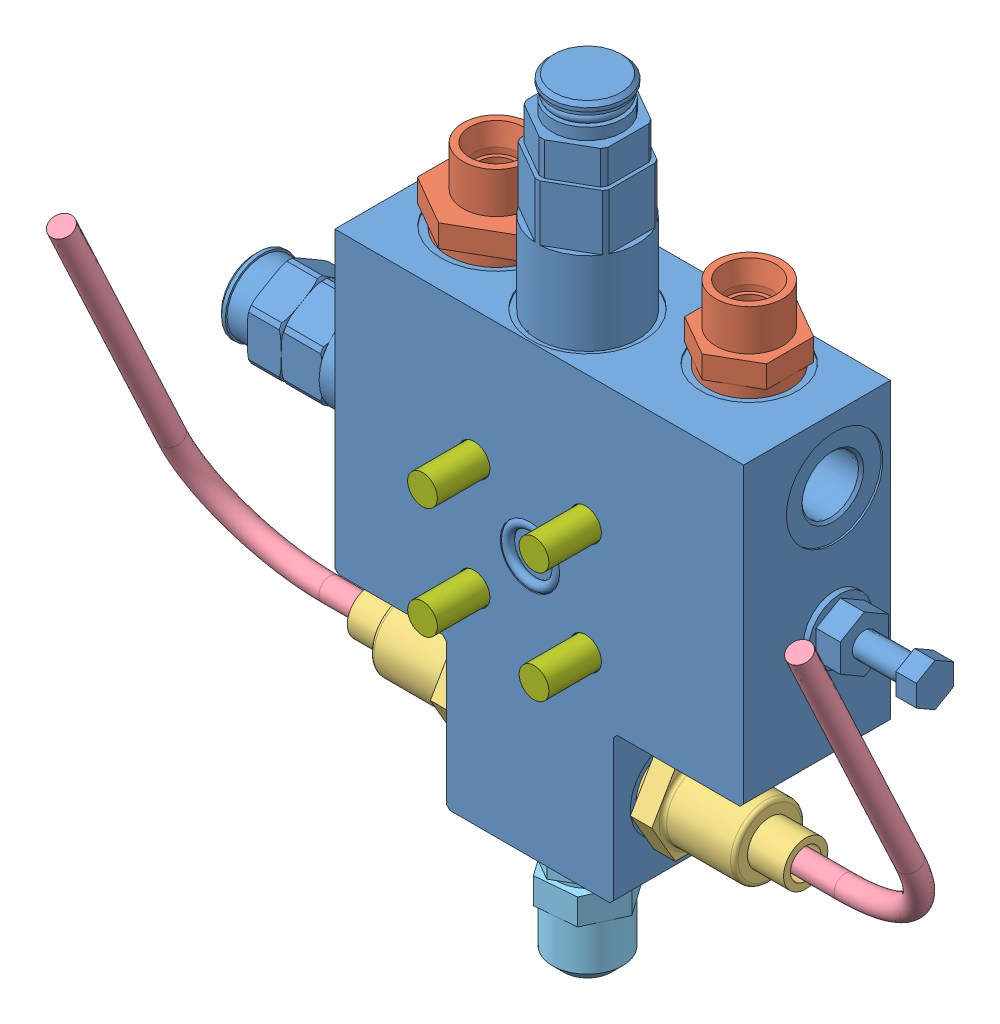
SolidWorks assembly Lastholdeventil Vip 55227 med dele, configuration Default. Lengths in mm.
Overall size (204.6 206.3 75.88).
16 component instances, 7 part files, 49 mates.
Components (placement in the parent):
- 55227-1: 55227 [Default] at origin size (183 174.8 39.85)
- Lige forskruninger-1: Lige forskruninger [P-GEV 12 LR-WD - 25127] at (87 58.5 0) x (1 0 0) z (0 -1 0) size (22 25.4 32)
- Lige forskruninger-2: Lige forskruninger [P-GES 12 LR 1-2 - WD - 25108] at (21 58.5 2) x (1 0 0) z (0 -1 0) size (27 31.18 34)
- 28850-1: 28850 [Default] at (111.2 -50 9) x (-1 0 0) z (0 0 1) size (47.5 21.71 25)
- 28850-2: 28850 [Default] at (-6.2 -50 9) x (1 0 0) z (0 0 -1) size (47.5 21.71 25)
- Ledning-1: Ledning [Default] at (3.2 -50 9) x (0 -0.422618 0.906308) z (1 0 0) size (6 103 53)
- Ledning-2: Ledning [Default] at (101.8 -50 9) x (0 0.422618 -0.906308) z (-1 0 0) size (6 103 53)
- Testnippel-1: Testnippel [26103] at (52.5 -77.5 9) x (1 0 0) z (0 1 0) size (21.85 21.94 41.5)
- Skiver-1: Skiver [Planskive 8mm A2 - 31147] at (67.5 -15 -15) x (1 0 0) z (0 0 -1) size (16 16 1.6)
- Skiver-2: Skiver [Planskive 8mm A2 - 31147] at (67.5 15 -15) x (1 0 0) z (0 0 -1) size (16 16 1.6)
- Skiver-3: Skiver [Planskive 8mm A2 - 31147] at (37.5 15 -15) x (1 0 0) z (0 0 -1) size (16 16 1.6)
- Skiver-4: Skiver [Planskive 8mm A2 - 31147] at (37.5 -15 -15) x (1 0 0) z (0 0 -1) size (16 16 1.6)
- Stålbolte-1: Stålbolte [M8 x 55 Rustfri - 30140] at (67.5 -15 -21.9) x (-1 0 0) z (0 0 1) size (15.01 13 60.3)
- Stålbolte-2: Stålbolte [M8 x 55 Rustfri - 30140] at (67.5 15 -21.9) x (-1 0 0) z (0 0 1) size (15.01 13 60.3)
- Stålbolte-3: Stålbolte [M8 x 55 Rustfri - 30140] at (37.5 15 -21.9) x (-1 0 0) z (0 0 1) size (15.01 13 60.3)
- Stålbolte-4: Stålbolte [M8 x 55 Rustfri - 30140] at (37.5 -15 -21.9) x (-0.5 -0.866025 0) z (0 0 1) size (15.01 13 60.3)
Mates (geometry in assembly coordinates):
- Concentric1: concentric anti-aligned: cylinder of 28850-1 through (111.2 -50 9) axis (1 0 0) radius 6.5; cylinder of 55227-1 through (16.858 -50 9) axis (-1 0 0) radius 5.9
- Coincident1: coincident anti-aligned: plane of 28850-1 through (74.5 -56.5 9) normal (-1 0 0); plane of 55227-1 through (74.5 -43.4 9) normal (1 0 0)
- Concentric2: concentric aligned: cylinder of 55227-1 through (16.858 -50 9) axis (-1 0 0) radius 5.9; cylinder of 28850-2 through (-6.2 -50 9) axis (-1 0 0) radius 6.5
- Coincident2: coincident anti-aligned: plane of 55227-1 through (30.5 -43.4 9) normal (-1 0 0); plane of 28850-2 through (30.5 -56.5 9) normal (1 0 0)
- Coincident3: coincident anti-aligned: plane of 55227-1 through (52.5 -69.5 15.6) normal (0 -1 0); plane of Testnippel-1 through (52.5 -69.5 9) normal (0 1 0)
- Concentric3: concentric anti-aligned: cylinder of 55227-1 through (52.5 -30 9) axis (0 1 0) radius 5.9; cylinder of Testnippel-1 through (52.5 -60 9) axis (0 -1 0) radius 6.5785
- Coincident5: coincident anti-aligned: plane of 28850-1 through (101.8 -54.1 9) normal (1 0 0); plane of Ledning-2 through (101.8 -50 9) normal (-1 0 0)
- Concentric5: concentric anti-aligned: cylinder of 28850-1 through (111.2 -50 9) axis (1 0 0) radius 4.1; cylinder of Ledning-2 through (121.8 -50 9) axis (-1 0 0) radius 3
- Concentric6: concentric anti-aligned: cylinder of 28850-2 through (-6.2 -50 9) axis (-1 0 0) radius 4.1; cylinder of Ledning-1 through (-16.8 -50 9) axis (1 0 0) radius 3
- Coincident6: coincident anti-aligned: plane of 28850-2 through (3.2 -54.1 9) normal (-1 0 0); plane of Ledning-1 through (3.2 -50 9) normal (1 0 0)
- Coincident7: coincident anti-aligned: plane of Ledning-1 through (3.2 -50 9) normal (0 -0.422618 0.906308); plane of Ledning-2 through (101.8 -50 9) normal (0 0.422618 -0.906308)
- Concentric7: concentric anti-aligned: cylinder of Skiver-1 through (67.5 -15 -16.6) axis (0 0 1) radius 8; cylinder of Stålbolte-1 through (67.5 -15 38.4) axis (0 0 -1) radius 4
- Coincident8: coincident anti-aligned: plane of Skiver-1 through (67.5 -15 -16.6) normal (0 0 -1); plane of Stålbolte-1 through (63.7472 -8.5 -16.6) normal (0 0 1)
- Concentric8: concentric anti-aligned: cylinder of Skiver-2 through (67.5 15 -16.6) axis (0 0 1) radius 8; cylinder of Stålbolte-2 through (67.5 15 38.4) axis (0 0 -1) radius 4
- Coincident9: coincident anti-aligned: plane of Skiver-2 through (67.5 15 -16.6) normal (0 0 -1); plane of Stålbolte-2 through (63.7472 21.5 -16.6) normal (0 0 1)
- Concentric9: concentric anti-aligned: cylinder of Skiver-3 through (37.5 15 -16.6) axis (0 0 1) radius 4.2; cylinder of Stålbolte-3 through (37.5 15 38.4) axis (0 0 -1) radius 4
- Coincident10: coincident anti-aligned: plane of Skiver-3 through (37.5 15 -16.6) normal (0 0 -1); plane of Stålbolte-3 through (33.7472 21.5 -16.6) normal (0 0 1)
- Coincident11: coincident anti-aligned: plane of Skiver-4 through (37.5 -15 -16.6) normal (0 0 -1); plane of Stålbolte-4 through (29.9944 -15 -16.6) normal (0 0 1)
- Coincident12: coincident aligned: plane of 55227-1 through (0 0 0) normal (0 0 1); plane of assembly through (0 0 0) normal (0 0 1)
- Coincident13: coincident aligned: plane of 55227-1 through (0 0 0) normal (0 1 0); plane of assembly through (0 0 0) normal (0 1 0)
- Coincident14: coincident aligned: plane of 55227-1 through (0 0 0) normal (1 0 0); plane of assembly through (0 0 0) normal (1 0 0)
- Concentric10: concentric anti-aligned: cylinder of 55227-1 through (87 12.903 0) axis (0 -1 0) radius 7.625; cylinder of Lige forskruninger-1 through (87 37.5 0) axis (0 1 0) radius 8.331
- Coincident15: coincident anti-aligned: plane of 55227-1 through (87 49.5 -13) normal (0 1 0); plane of Lige forskruninger-1 through (87 49.5 0) normal (0 -1 0)
- Concentric11: concentric aligned: cylinder of 55227-1 through (21 57.522 2) axis (0 1 0) radius 9.5; cylinder of Lige forskruninger-2 through (21 35.5 2) axis (0 1 0) radius 10.4975
- Coincident16: coincident anti-aligned: plane of 55227-1 through (21 49.5 -8.2) normal (0 1 0); plane of Lige forskruninger-2 through (21 49.5 2) normal (0 -1 0)
- Coincident17: coincident anti-aligned: plane of 28850-1 through (111.2 -50 9) normal (0 0 1); plane of 28850-2 through (-6.2 -50 9) normal (0 0 -1)
- Coincident18: coincident aligned: plane of Lige forskruninger-1 through (87 58.5 0) normal (0 0 1); plane of assembly through (0 0 0) normal (0 0 1)
- Parallel1: parallel aligned: plane of Lige forskruninger-2 through (21 58.5 2) normal (0 0 1); plane of assembly through (0 0 0) normal (0 0 1)
- Parallel2: parallel anti-aligned: plane of 28850-1 through (111.2 -50 9) normal (0 -1 0); plane of assembly through (0 0 0) normal (0 1 0)
- Coincident23: coincident aligned: plane of Ledning-1 through (3.2 -50 9) normal (0 -0.906308 -0.422618); plane of Ledning-2 through (101.8 -50 9) normal (0 -0.906308 -0.422618)
- Angle2: planar angle = 2.007129 rad aligned: plane of Ledning-1 through (3.2 -50 9) normal (0 -0.906308 -0.422618); plane of assembly through (0 0 0) normal (0 0 1)
- Parallel4: parallel anti-aligned: plane of Testnippel-1 through (52.5 -77.5 9) normal (0 0 -1); plane of assembly through (0 0 0) normal (0 0 1)
- Concentric12: concentric anti-aligned: cylinder of 55227-1 through (67.5 -15 -15) axis (0 0 1) radius 4.25; cylinder of Stålbolte-1 through (67.5 -15 38.4) axis (0 0 -1) radius 4
- Concentric13: concentric anti-aligned: cylinder of 55227-1 through (67.5 15 -15) axis (0 0 1) radius 4.25; cylinder of Stålbolte-2 through (67.5 15 38.4) axis (0 0 -1) radius 4
- Concentric14: concentric anti-aligned: cylinder of 55227-1 through (37.5 -15 -15) axis (0 0 1) radius 4.25; cylinder of Stålbolte-4 through (37.5 -15 38.4) axis (0 0 -1) radius 4
- Concentric15: concentric anti-aligned: cylinder of 55227-1 through (37.5 15 -15) axis (0 0 1) radius 4.25; cylinder of Stålbolte-3 through (37.5 15 38.4) axis (0 0 -1) radius 4
- Concentric16: concentric anti-aligned: cylinder of Skiver-4 through (37.5 -15 -16.6) axis (0 0 1) radius 4.2; cylinder of Stålbolte-4 through (37.5 -15 38.4) axis (0 0 -1) radius 4
- Coincident26: coincident anti-aligned: plane of 55227-1 through (110 50 -15) normal (0 0 -1); plane of Skiver-1 through (67.5 -15 -15) normal (0 0 1)
- Coincident27: coincident anti-aligned: plane of 55227-1 through (110 50 -15) normal (0 0 -1); plane of Skiver-2 through (67.5 15 -15) normal (0 0 1)
- Coincident28: coincident anti-aligned: plane of 55227-1 through (110 50 -15) normal (0 0 -1); plane of Skiver-4 through (37.5 -15 -15) normal (0 0 1)
- Coincident29: coincident anti-aligned: plane of 55227-1 through (110 50 -15) normal (0 0 -1); plane of Skiver-3 through (37.5 15 -15) normal (0 0 1)
- Parallel5: parallel aligned: plane of Stålbolte-2 through (59.9944 15 -16.6) normal (-0.866025 -0.5 0); plane of Stålbolte-3 through (29.9944 15 -16.6) normal (-0.866025 -0.5 0)
- Parallel6: parallel aligned: plane of Stålbolte-2 through (59.9944 15 -16.6) normal (-0.866025 -0.5 0); plane of Stålbolte-1 through (59.9944 -15 -16.6) normal (-0.866025 -0.5 0)
- Parallel7: parallel aligned: plane of Stålbolte-2 through (59.9944 15 -16.6) normal (-0.866025 -0.5 0); plane of Stålbolte-4 through (29.9944 -15 -16.6) normal (-0.866025 -0.5 0)
- Parallel8: parallel aligned: plane of Skiver-1 through (67.5 -15 -15) normal (0 -1 0); plane of Skiver-2 through (67.5 15 -15) normal (0 -1 0)
- Parallel9: parallel aligned: plane of Skiver-1 through (67.5 -15 -15) normal (0 -1 0); plane of Skiver-3 through (37.5 15 -15) normal (0 -1 0)
- Parallel10: parallel aligned: plane of Skiver-1 through (67.5 -15 -15) normal (0 -1 0); plane of Skiver-4 through (37.5 -15 -15) normal (0 -1 0)
- Parallel11: parallel anti-aligned: plane of Stålbolte-1 through (67.5 -15 -21.9) normal (0 -1 0); plane of assembly through (0 0 0) normal (0 1 0)
- Parallel12: parallel anti-aligned: plane of Skiver-1 through (67.5 -15 -15) normal (0 -1 0); plane of assembly through (0 0 0) normal (0 1 0)
